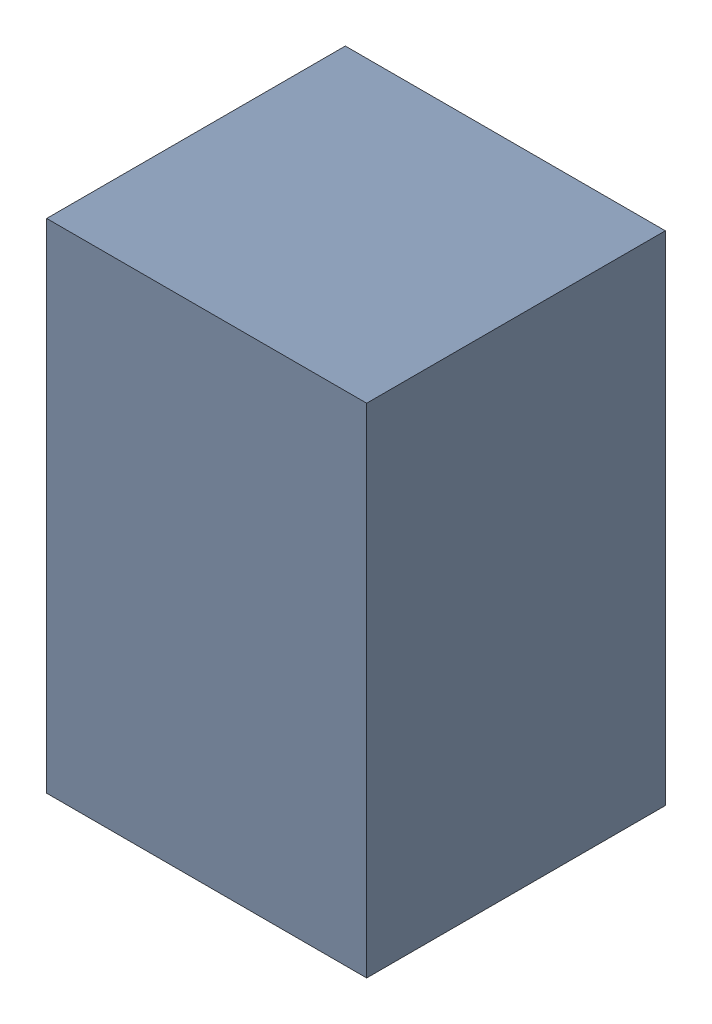
SolidWorks assembly C2, configuration Default. Lengths in mm.
Overall size (1.35 2.1 1.26).
2 component instances, 1 part files, 0 mates.
Components (placement in the parent):
- 407985696-1: 407985696 [Default] at (23.114 61.722 0.0127) size (1.35 2.1 1.26)
  - Extruded_1-1: Extruded_1 [Default] at origin size (1.35 2.1 1.26)
